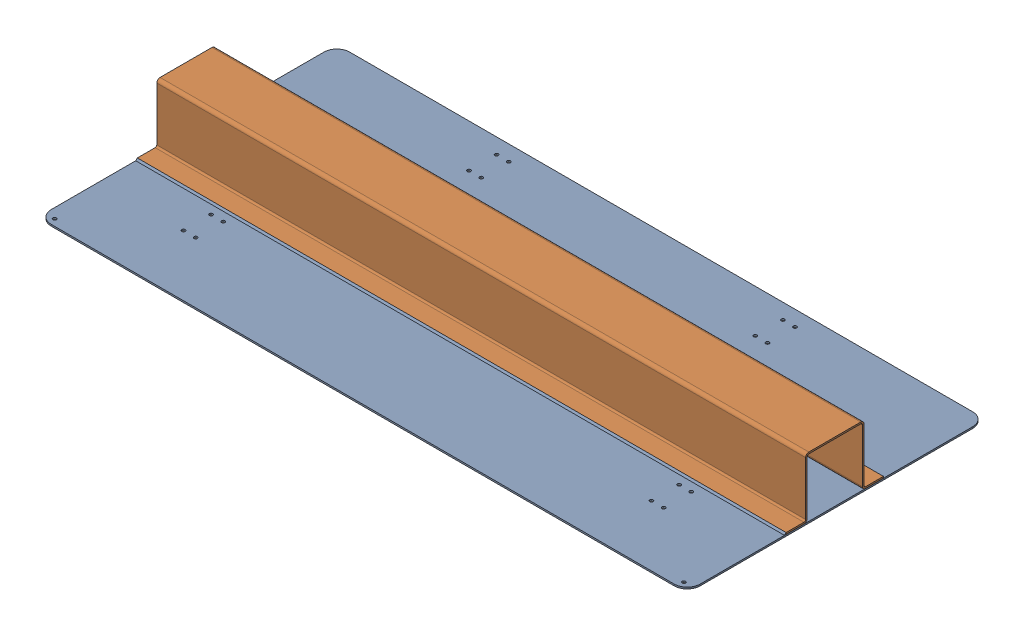
SolidWorks assembly GE-16081_ASM, configuration Default. Lengths in mm.
Overall size (1270 120.65 584.2).
3 component instances, 3 part files, 0 mates.
Components (placement in the parent):
- GE-16081_ASM-1: GE-16081_ASM [Default] at origin size (1270 3.17 196.85)
- GE-16016-1: GE-16016 [Default] at origin size (1270 3.17 584.2)
- GE-16081-01-1: GE-16081-01 [Default] at (0 6.35 0) x (1 0 0) z (0 -1 0) size (1270 190.5 117.48)
